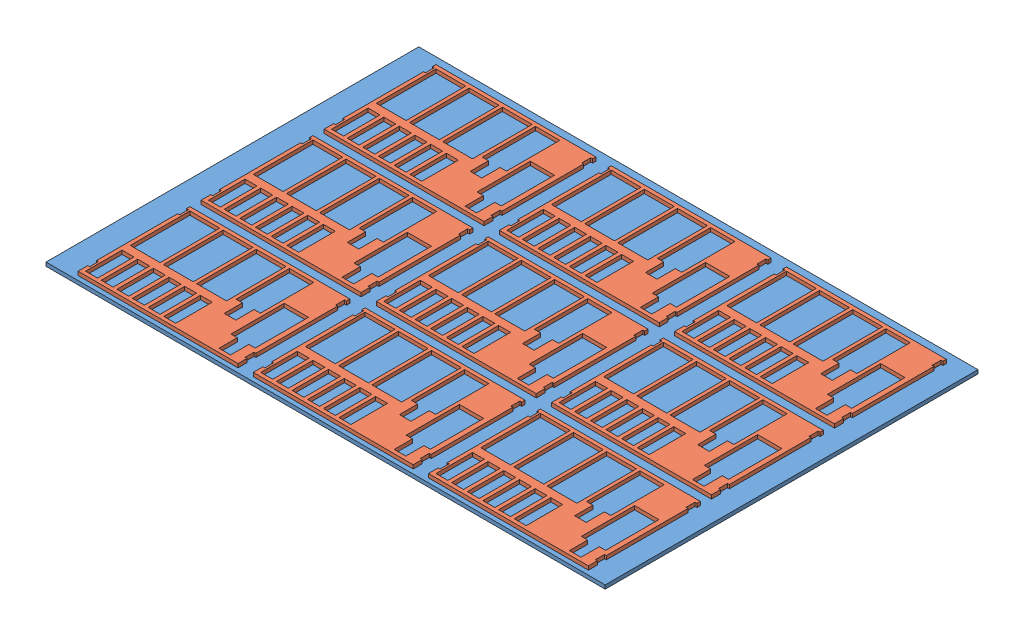
SolidWorks assembly final-kaf-9, configuration Default. Lengths in mm.
Overall size (1500 20 1000).
10 component instances, 2 part files, 3 mates.
Components (placement in the parent):
- plate-1: plate [Default] at origin size (1500 10 1000)
- double-kaf-1: double-kaf [Default] at (-461.1697 20 -321.7157) size (429 10 300)
- double-kaf-2: double-kaf [Default] at (-461.1697 20 8.2843) size (429 10 300)
- double-kaf-3: double-kaf [Default] at (-461.1697 20 338.2843) size (429 10 300)
- double-kaf-4: double-kaf [Default] at (8.8303 20 -321.7157) size (429 10 300)
- double-kaf-5: double-kaf [Default] at (8.8303 20 8.2843) size (429 10 300)
- double-kaf-6: double-kaf [Default] at (8.8303 20 338.2843) size (429 10 300)
- double-kaf-7: double-kaf [Default] at (478.8303 20 -321.7157) size (429 10 300)
- double-kaf-8: double-kaf [Default] at (478.8303 20 8.2843) size (429 10 300)
- double-kaf-9: double-kaf [Default] at (478.8303 20 338.2843) size (429 10 300)
Mates (geometry in assembly coordinates):
- Coincident1: coincident anti-aligned: plane of plate-1 through (0 10 0) normal (0 1 0); plane of double-kaf-1 through (-461.1697 10 -321.7157) normal (0 -1 0)
- Distance1: distance = 30 mm: line of double-kaf-1 through (-246.6697 20 -471.7157) axis (-1 0 0); line of plate-1 through (750 10 -500) axis (-1 0 0)
- Distance2: distance = 75 mm: line of double-kaf-1 through (-675.6697 20 -438.7157) axis (0 0 1); line of plate-1 through (-750 10 -500) axis (0 0 1)
